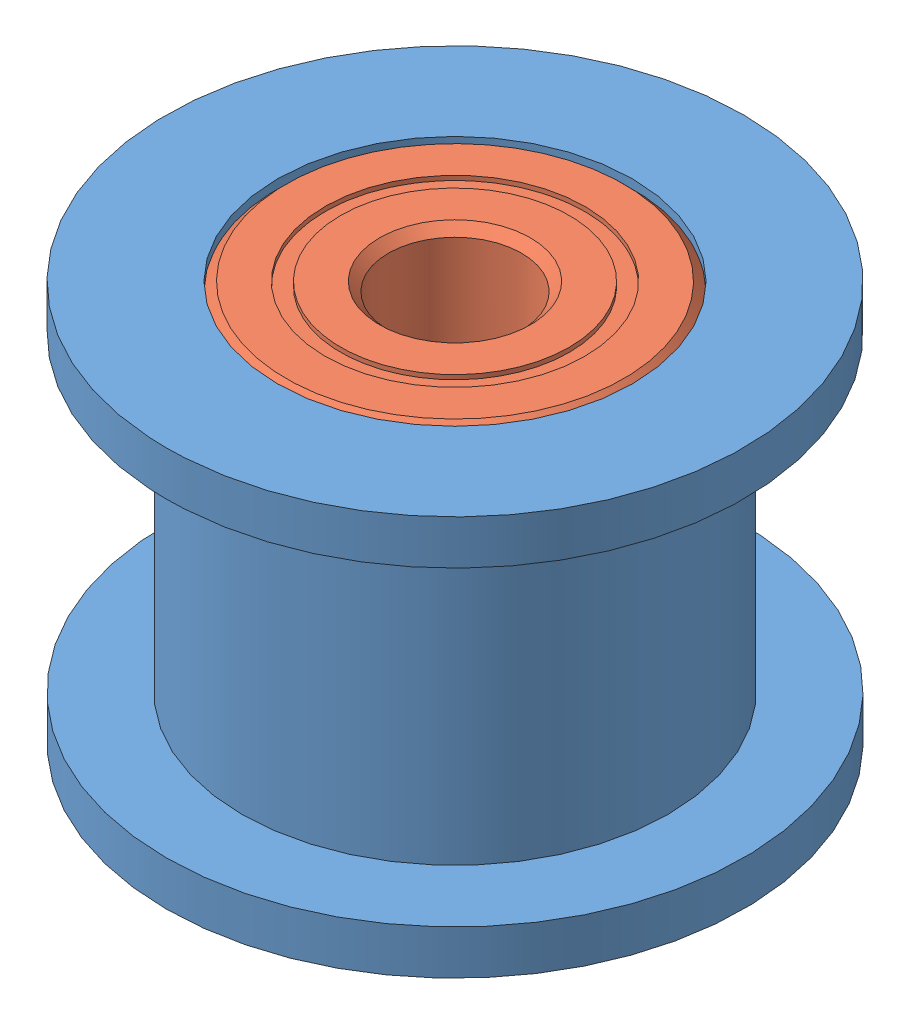
SolidWorks assembly 1021795, configuration Default. Lengths in mm.
Overall size (13 9 13).
3 component instances, 2 part files, 5 mates.
Components (placement in the parent):
- 1021795-IDLER PULLEY-1: 1021795-IDLER PULLEY [Default] at origin size (13 9 13)
- 1021795-693-2Z BEARING, 8 mm OD, 3 mm ID, 4 mm WIDTH-1: 1021795-693-2Z BEARING, 8 mm OD, 3 mm ID, 4 mm WIDTH [DEFAULT] at (0 2.5 0) x (-0.422593 0 0.90632) z (0 -1 0) size (8 8 4)
- 1021795-693-2Z BEARING, 8 mm OD, 3 mm ID, 4 mm WIDTH-2: 1021795-693-2Z BEARING, 8 mm OD, 3 mm ID, 4 mm WIDTH [DEFAULT] at (0 -2.5 0) x (0.989142 0 -0.14696) z (0 -1 0) size (8 8 4)
Mates (geometry in assembly coordinates):
- Coincident1: coordinate: point of 1021795-IDLER PULLEY-1
- Concentric1: concentric anti-aligned: cylinder of 1021795-IDLER PULLEY-1 through (0 -4.5 0) axis (0 1 0) radius 2; cylinder of 1021795-693-2Z BEARING, 8 mm OD, 3 mm ID, 4 mm WIDTH-1 through (0 0.5 0) axis (0 -1 0) radius 1.5
- Coincident2: coincident anti-aligned: plane of 1021795-IDLER PULLEY-1 through (0 0.5 0) normal (0 1 0); plane of 1021795-693-2Z BEARING, 8 mm OD, 3 mm ID, 4 mm WIDTH-1 through (-3.444 0.5 -1.6059) normal (0 -1 0)
- Concentric2: concentric anti-aligned: cylinder of 1021795-IDLER PULLEY-1 through (0 -4.5 0) axis (0 1 0) radius 2; cylinder of 1021795-693-2Z BEARING, 8 mm OD, 3 mm ID, 4 mm WIDTH-2 through (0 -4.5 0) axis (0 -1 0) radius 1.5
- Coincident3: coincident anti-aligned: plane of 1021795-IDLER PULLEY-1 through (0 -0.5 0) normal (0 -1 0); plane of 1021795-693-2Z BEARING, 8 mm OD, 3 mm ID, 4 mm WIDTH-2 through (0.5584 -0.5 3.7587) normal (0 1 0)
